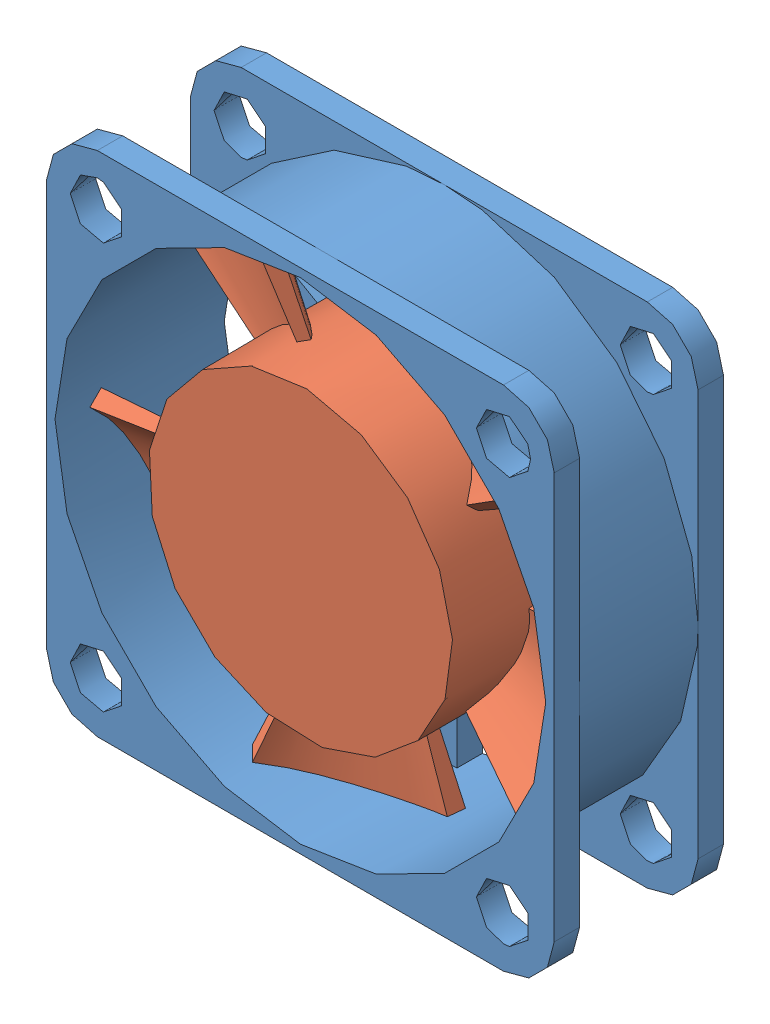
SolidWorks assembly Fan-DC-KDE0503PFB3-Promoco, configuration Fan-DC-KDE0503PFB3-Promoco. Lengths in mm.
Overall size (30 30 10).
2 component instances, 2 part files, 2 mates.
Components (placement in the parent):
- Fan-House-30x30x10-Promoco-1: Fan-House-30x30x10-Promoco [Fan-House-KDE0503PFB3-Promoco] at origin size (30 30 10)
- Fan-30x30x10-Promoco-1: Fan-30x30x10-Promoco [Fan-KDE0503PFB3-Promoco] x (0 0 -1) z (-0.999131 0.04169 0) size (8.5 27.91 28)
Mates (geometry in assembly coordinates):
- Coincident1: coincident anti-aligned: plane of Fan-House-30x30x10-Promoco-1 through (0 0 0) normal (0 0 1); plane of Fan-30x30x10-Promoco-1
- Coincident2: coincident aligned: axis of Fan-30x30x10-Promoco-1 through (0 0 12.1385) axis (0 0 -1); axis of Fan-House-30x30x10-Promoco-1 through (0 0 10) axis (0 0 -1)
